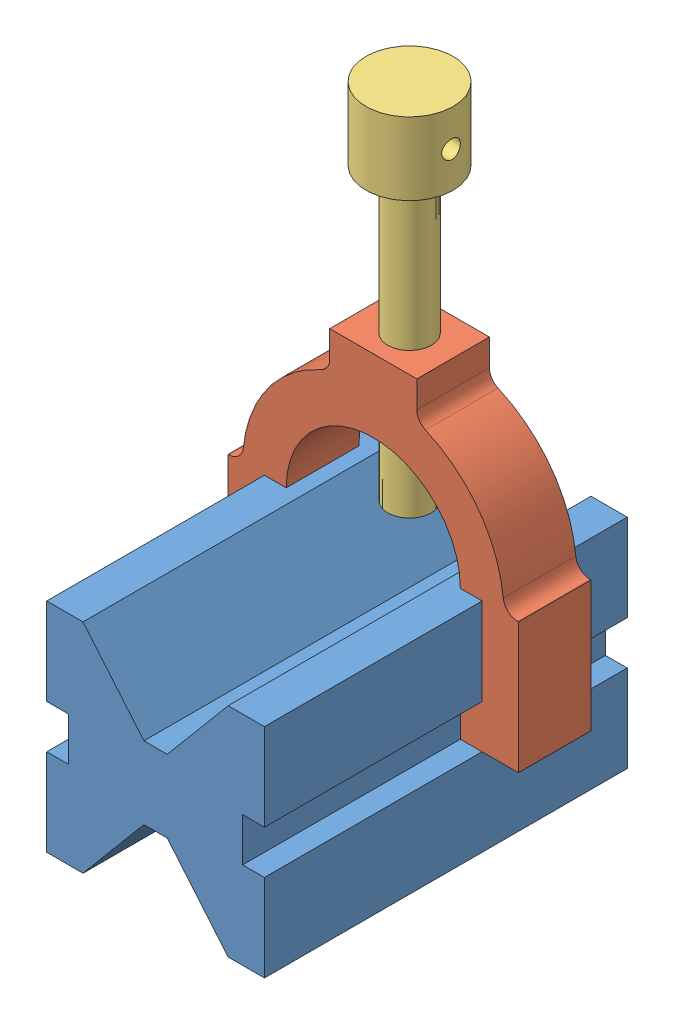
SolidWorks assembly darmaly-LAB11-Assembly, configuration Default. Lengths in mm.
Overall size (80 164 100).
3 component instances, 3 part files, 5 mates.
Components (placement in the parent):
- Base-1: Base [Default] at origin size (60 60 100)
- Yoke-1: Yoke [Default] at (-10 24 -60) size (80 80 20)
- Pin-1: Pin [Default] at (30 64 -70) x (0.999644 0 0.026688) z (-0.026688 0 0.999644) size (24 100 24)
Mates (geometry in assembly coordinates):
- Coincident1: coincident anti-aligned: plane of Base-1 through (54 36 -100) normal (1 0 0); plane of Yoke-1 through (54 24 -80) normal (-1 0 0)
- Coincident2: coincident anti-aligned: plane of Base-1 through (0 60 -100) normal (0 1 0); plane of Yoke-1 through (60 60 -80) normal (0 -1 0)
- Distance1: distance = 60 mm aligned: plane of Yoke-1 through (-10 24 -60) normal (0 0 1); plane of Base-1 through (0 0 0) normal (0 0 1)
- Concentric1: concentric: cylinder of Yoke-1 through (30 24 -70) axis (0 1 0) radius 6; cylinder of Pin-1 through (30 -921.544 -70) axis (0 -1 0) radius 6
- Distance4: distance = 40 mm anti-aligned: plane of Pin-1 through (35.9979 144 -69.8399) normal (0 -1 0); plane of Yoke-1 through (-10 104 -80) normal (0 1 0)
